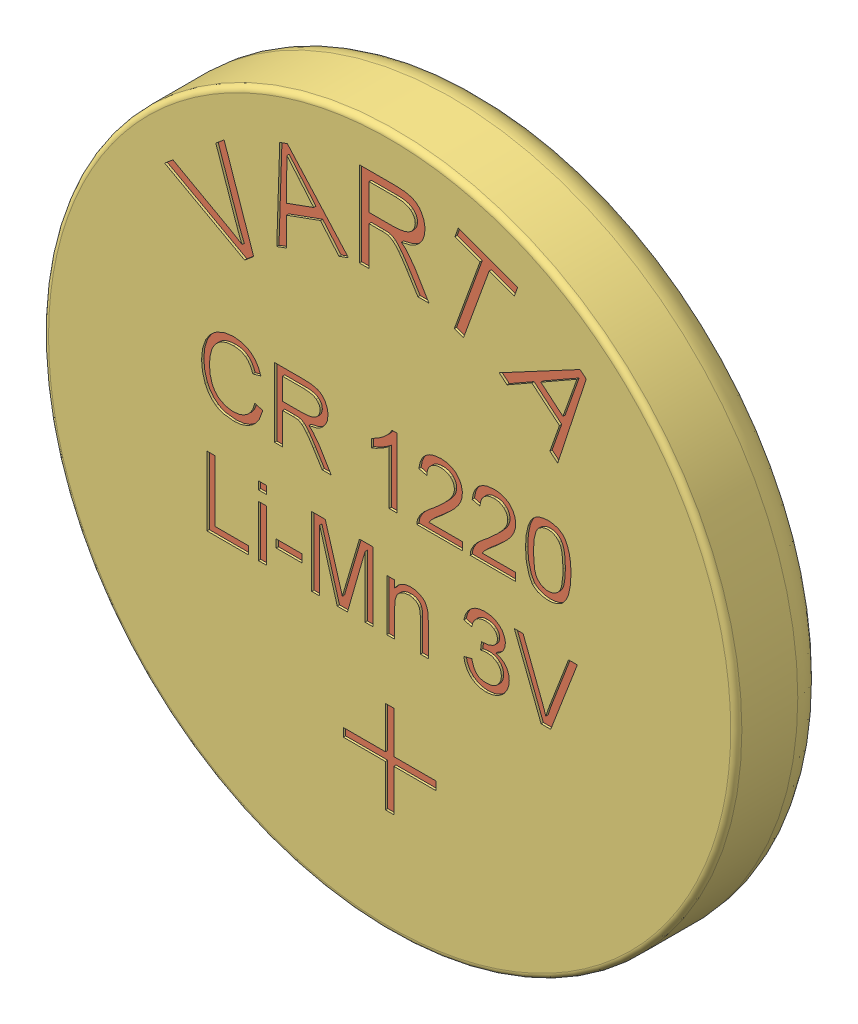
SolidWorks assembly User Library-CR1220-2, configuration Default. Lengths in mm.
Overall size (12.4 12.4 2.01).
3 component instances, 3 part files, 0 mates.
Components (placement in the parent):
- User Library-CR1220-2_refine_Revolution001-1: User Library-CR1220-2_refine_Revolution001 [Default] at (0 0 2) x (1 0 0) z (0 1 0) size (11.2 0.85 11.2)
- User Library-CR1220-2_Cut003-1: User Library-CR1220-2_Cut003 [Default] at origin size (7.54 9.76 0.06)
- User Library-CR1220-2_refine_Cut001-1: User Library-CR1220-2_refine_Cut001 [Default] at (0 0 2) x (1 0 0) z (0 1 0) size (12.4 2.01 12.4)
